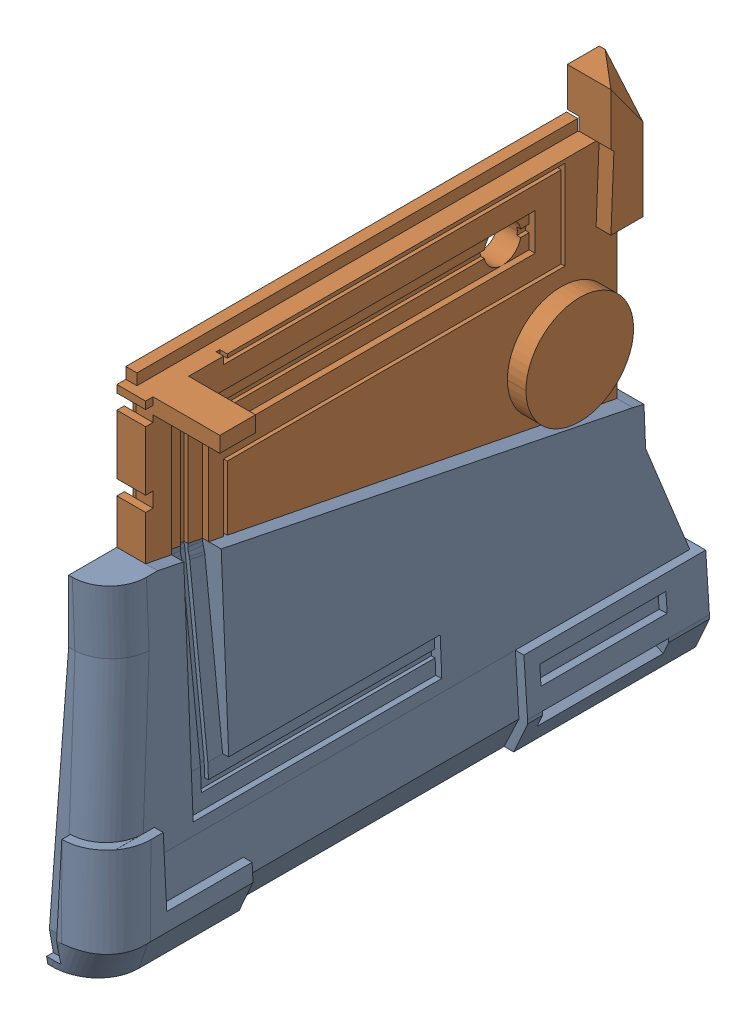
SolidWorks assembly body-left-split, configuration Default. Lengths in mm.
Overall size (42.92 238.33 272.05).
2 component instances, 2 part files, 1 mates.
Components (placement in the parent):
- body-left-bottom-1: body-left-bottom [Default] at origin size (28.33 151.67 272.05)
- body-left-top-1: body-left-top [Default] at origin size (42.92 128.17 216.67)
Mates (geometry in assembly coordinates):
- Coincident1: coincident anti-aligned: circle of body-left-bottom-1; circle of body-left-top-1
